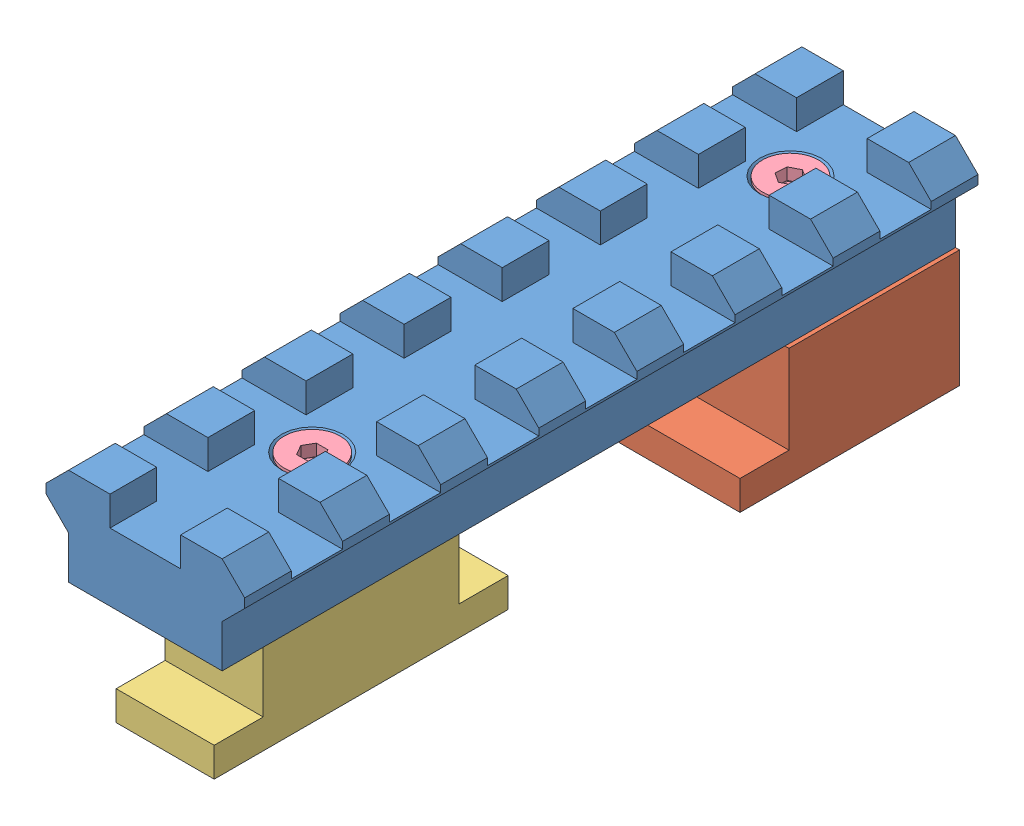
SolidWorks assembly Baugruppe1, configuration Standard. Lengths in mm.
Overall size (20.27 21.9 74.82).
5 component instances, 4 part files, 9 mates.
Components (placement in the parent):
- Rail-3: Rail [Standard] at (-4.1271 5.1584 0) size (20.27 9.9 74.82)
- flip_back-3: flip_back [Standard] at (-4.1271 -4.7457 0) x (0 0 1) z (-1 0 0) size (22.4 12 16.5)
- flip_front-1: flip_front [Standard] at (-4.1271 -4.7457 57.8) x (0 0 -1) z (1 0 0) size (30 12 10)
- Socket Countersunk Head Screw_DIN-6: Socket Countersunk Head Screw_DIN [DIN 7991 - M3 x 16 --- 12.8S] at (-4.1271 2.1584 57.8) x (0 -1 0) z (0 0 1) size (16 5.7 5.7)
- Socket Countersunk Head Screw_DIN-7: Socket Countersunk Head Screw_DIN [DIN 7991 - M3 x 16 --- 12.8S] at (-4.1271 2.1584 9) x (0 -1 0) z (-0.546944 0 0.837169) size (16 5.7 5.7)
Mates (geometry in assembly coordinates):
- Deckungsgleich6: coincident: moEndPointRef_w of Rail-3; moEndPointRef_w of flip_back-3
- Deckungsgleich7: coincident anti-aligned: plane of Rail-3 through (-11.963 -4.7457 74.824) normal (0 -1 0); plane of flip_back-3 through (-12.3771 -4.7457 0) normal (0 1 0)
- Deckungsgleich8: coincident anti-aligned: line of Rail-3 through (-11.963 -4.7457 0) axis (1 0 0); line of flip_back-3 through (4.1229 -4.7457 0) axis (-1 0 0)
- Deckungsgleich11: coincident anti-aligned: plane of Rail-3 through (-11.963 -4.7457 74.824) normal (0 -1 0); plane of flip_front-1 through (0.8729 -4.7457 72.8) normal (0 1 0)
- Konzentrisch1: concentric aligned: cone of Rail-3 through (-4.1271 2.1584 9) axis (0 -1 0); cone of Socket Countersunk Head Screw_DIN-7 through (-4.1271 1.8084 9) axis (0 -1 0)
- Deckungsgleich12: coincident aligned: plane of Rail-3 through (-7.7316 2.1584 74.824) normal (0 1 0); plane of Socket Countersunk Head Screw_DIN-7 through (-4.1271 2.1584 9) normal (0 1 0)
- Konzentrisch3: concentric aligned: cone of Rail-3 through (-4.1271 2.1612 57.8) axis (0 -1 0); cone of Socket Countersunk Head Screw_DIN-6 through (-4.1271 1.8084 57.8) axis (0 -1 0)
- Deckungsgleich13: coincident aligned: plane of Rail-3 through (-7.7316 2.1584 74.824) normal (0 1 0); plane of Socket Countersunk Head Screw_DIN-6 through (-4.1271 2.1584 57.8) normal (0 1 0)
- Konzentrisch5: concentric aligned: cylinder of Rail-3 through (-4.1271 5.1584 57.8) axis (0 1 0) radius 1.7; cylinder of flip_front-1 through (-4.1271 -4.7457 57.8) axis (0 1 0) radius 1.25
